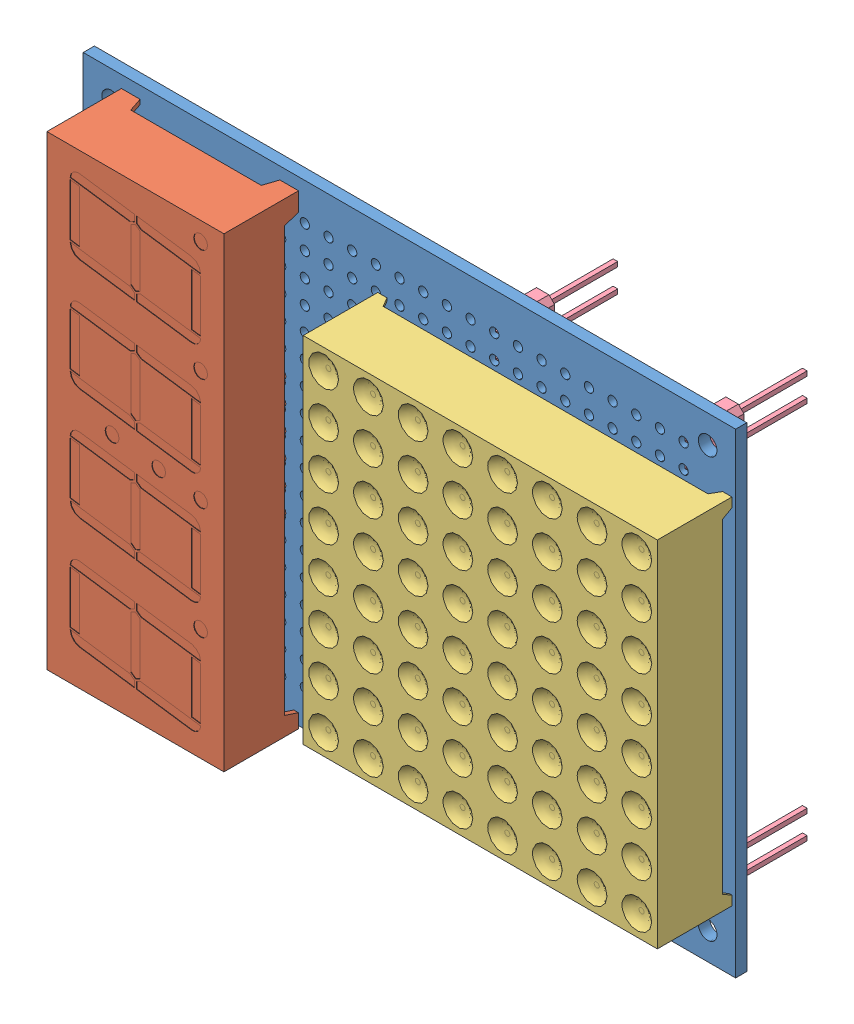
SolidWorks assembly LedModule, configuration  . Lengths in mm.
Overall size (70 51.1 21.4).
7 component instances, 4 part files, 20 mates.
Components (placement in the parent):
- ProtoBoard_70x50-1: ProtoBoard_70x50 [ ] at (-91.7305 -48.7451 8.1292) size (70 51 1.2)
- 7Seg_Led_5641BH-1: 7Seg_Led_5641BH [ ] at (-77.9305 -23.8451 9.5292) x (0 1 0) z (0 0 1) size (50 19 10.5)
- Led_Matrix_1588BS-1: Led_Matrix_1588BS [Default] at (-41.1305 -23.2451 13.3292) x (0 -1 0) z (-1 0 0) size (38 12.5 38)
- 2.54 pitch pin-1: 2.54 pitch pin [2] at (-27.3105 -1.7451 6.4192) x (-1 0 0) z (0 -1 0) size (2.54 13 5.08)
- 2.54 pitch pin-2: 2.54 pitch pin [2] at (-27.3105 -42.3851 6.4192) x (-1 0 0) z (0 -1 0) size (2.54 13 5.08)
- 2.54 pitch pin-3: 2.54 pitch pin [2] at (-47.6305 -1.7451 6.4192) x (-1 0 0) z (0 -1 0) size (2.54 13 5.08)
- 2.54 pitch pin-4: 2.54 pitch pin [2] at (-47.6305 -42.3851 6.4192) x (-1 0 0) z (0 -1 0) size (2.54 13 5.08)
Mates (geometry in assembly coordinates):
- Расстояние1: distance = 8.2 mm: plane of ProtoBoard_70x50-1 through (-91.7305 -48.7451 9.3292) normal (0 0 1); plane of 7Seg_Led_5641BH-1 through (-77.9305 -23.8451 17.5292) normal (0 0 1)
- Параллельность1: parallel: plane of ProtoBoard_70x50-1 through (-91.7305 -48.7451 9.3292) normal (-1 0 0); plane of 7Seg_Led_5641BH-1 through (-87.4305 1.1549 9.5292) normal (-1 0 0)
- Расстояние2: distance = 8 mm: plane of Led_Matrix_1588BS-1 through (-22.1305 -42.2451 17.3292) normal (0 0 1); plane of ProtoBoard_70x50-1 through (-91.7305 -48.7451 9.3292) normal (0 0 1)
- Параллельность2: parallel: plane of ProtoBoard_70x50-1 through (-21.7305 -48.7451 9.3292) normal (1 0 0); plane of Led_Matrix_1588BS-1 through (-22.1305 -4.2451 17.3292) normal (1 0 0)
- Расстояние3: distance = 8.3 mm: plane of Led_Matrix_1588BS-1 through (-60.1305 -4.2451 17.3292) normal (-1 0 0); plane of 7Seg_Led_5641BH-1 through (-68.4305 -48.8451 9.5292) normal (1 0 0)
- Расстояние5: distance = 4 mm: plane of 2.54 pitch pin-1 through (-27.3105 -1.7451 4.1292) normal (0 0 -1); plane of ProtoBoard_70x50-1 through (-91.7305 -48.7451 8.1292) normal (0 0 -1)
- Концентричный3: concentric: cylinder of ProtoBoard_70x50-1 through (-27.3105 -1.7451 9.3292) axis (0 0 -1) radius 0.5; line of 2.54 pitch pin-1 through (-27.3105 -1.7451 9.8385) axis (0 0 -1)
- Параллельность3: parallel: plane of ProtoBoard_70x50-1 through (-21.7305 -48.7451 9.3292) normal (1 0 0); plane of 2.54 pitch pin-1 through (-26.0405 -0.4751 4.1292) normal (1 0 0)
- Концентричный4: concentric: cylinder of ProtoBoard_70x50-1 through (-27.3105 -42.3851 9.3292) axis (0 0 -1) radius 0.5; line of 2.54 pitch pin-2 through (-27.3105 -42.3851 9.8385) axis (0 0 -1)
- Совпадение2: coincident: plane of 2.54 pitch pin-1 through (-27.3105 -4.2851 4.1292) normal (0 0 -1); plane of 2.54 pitch pin-2 through (-27.3105 -42.3851 4.1292) normal (0 0 -1)
- Параллельность4: parallel: plane of ProtoBoard_70x50-1 through (-21.7305 -48.7451 9.3292) normal (1 0 0); plane of 2.54 pitch pin-2 through (-26.0405 -41.1151 4.1292) normal (1 0 0)
- Концентричный5: concentric: circle of ProtoBoard_70x50-1; line of 2.54 pitch pin-3 through (-47.6305 -1.7451 9.8385) axis (0 0 -1)
- Совпадение3: coincident: plane of 2.54 pitch pin-1 through (-27.3105 -1.7451 4.1292) normal (0 0 -1); plane of 2.54 pitch pin-3 through (-47.6305 -1.7451 4.1292) normal (0 0 -1)
- Концентричный6: concentric: circle of ProtoBoard_70x50-1; line of 2.54 pitch pin-4 through (-47.6305 -42.3851 9.8385) axis (0 0 -1)
- Совпадение4: coincident: plane of 2.54 pitch pin-3 through (-47.6305 -4.2851 4.1292) normal (0 0 -1); plane of 2.54 pitch pin-4 through (-47.6305 -44.9251 4.1292) normal (0 0 -1)
- Параллельность5: parallel: plane of 2.54 pitch pin-1 through (-26.0405 -0.4751 4.1292) normal (1 0 0); plane of 2.54 pitch pin-3 through (-46.3605 -0.4751 4.1292) normal (1 0 0)
- Параллельность6: parallel: plane of 2.54 pitch pin-2 through (-26.0405 -41.1151 4.1292) normal (1 0 0); plane of 2.54 pitch pin-4 through (-46.3605 -41.1151 4.1292) normal (1 0 0)
- Расстояние6: distance = 0.1 mm: plane of ProtoBoard_70x50-1 through (-91.7305 -48.7451 9.3292) normal (0 -1 0); plane of 7Seg_Led_5641BH-1 through (-87.4305 -48.8451 9.5292) normal (0 -1 0)
- Расстояние7: distance = 4.3 mm: plane of ProtoBoard_70x50-1 through (-91.7305 -48.7451 9.3292) normal (-1 0 0); plane of 7Seg_Led_5641BH-1 through (-87.4305 1.1549 9.5292) normal (-1 0 0)
- Расстояние8: distance = 6.5 mm: plane of Led_Matrix_1588BS-1 through (-60.1305 -42.2451 17.3292) normal (0 -1 0); plane of ProtoBoard_70x50-1 through (-91.7305 -48.7451 9.3292) normal (0 -1 0)
